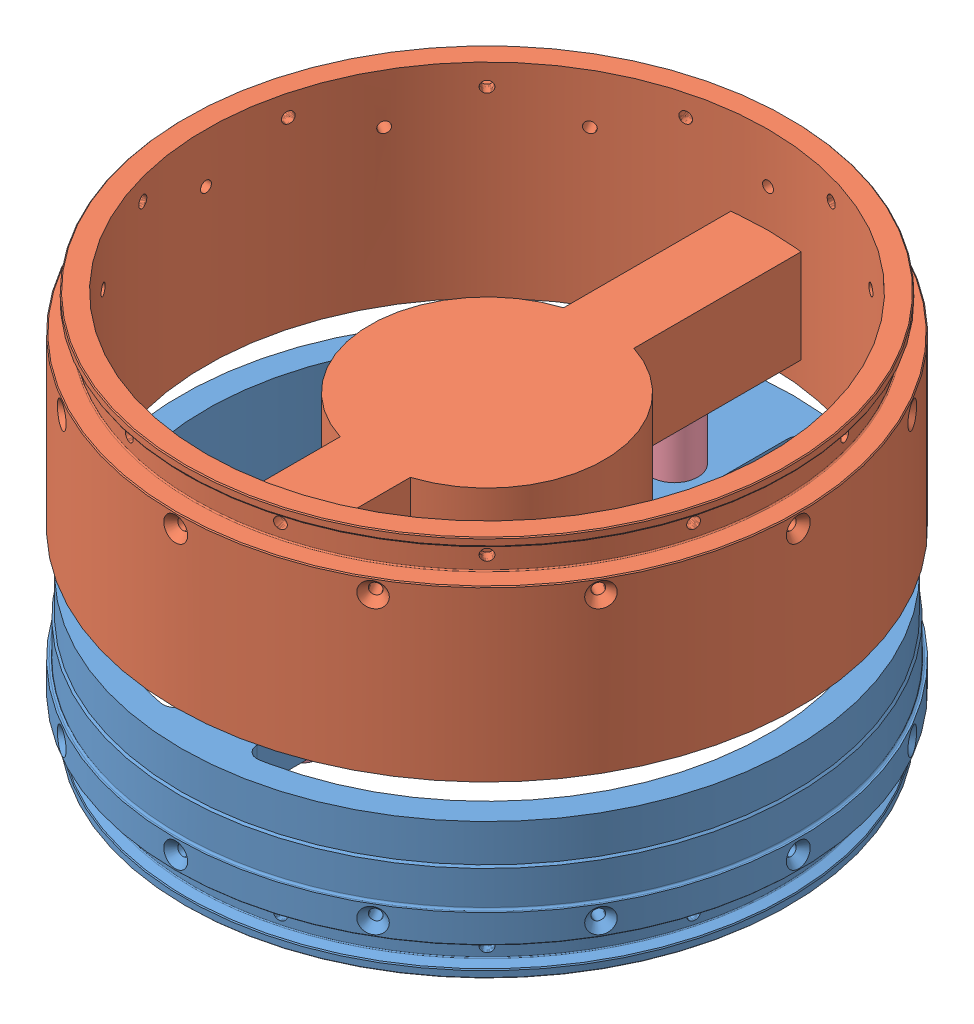
SolidWorks assembly Concept_Ring, configuration Default. Lengths in mm.
Overall size (168.91 103.49 168.91).
5 component instances, 4 part files, 8 mates.
Components (placement in the parent):
- Concept_Upper-1: Concept_Upper [Default] at (-11.1747 14.1513 -9.4137) size (168.91 37.68 168.91)
- Concept_Lower-1: Concept_Lower [Default] at (-11.1747 96.7282 -9.4137) x (-1 0 0) z (0 0 1) size (168.91 55.46 168.91)
- pretend_motor-1: pretend_motor [Default] at (-11.1747 77.1717 -9.4137) x (-0.757863 0 0.652414) z (0 1 0) size (38.1 38.1 55.13)
- Alignment_Pins-1: Alignment_Pins [Default] at (-11.1747 26.3217 -60.2137) size (12.7 50.8 12.7)
- Alignment_Pins-2: Alignment_Pins [Default] at (-11.1747 26.3217 41.3863) size (12.7 50.8 12.7)
Mates (geometry in assembly coordinates):
- Coincident1: coincident: circle of Concept_Lower-1; circle of pretend_motor-1
- Concentric1: concentric: cylinder of Concept_Lower-1 through (-11.1747 77.1217 -9.4137) axis (0 -1 0) radius 19.05; cylinder of pretend_motor-1 through (-11.1747 77.1217 -9.4137) axis (0 -1 0) radius 19.05
- Coincident2: coincident: circle of Concept_Lower-1; plane of Alignment_Pins-2 through (-11.1747 77.1217 41.3863) normal (0 1 0)
- Concentric3: concentric: cylinder of Concept_Lower-1 through (-11.1747 77.1217 41.3863) axis (0 -1 0) radius 6.35; cylinder of Alignment_Pins-2 through (-11.1747 77.1217 41.3863) axis (0 -1 0) radius 6.35
- Coincident3: coincident: plane of Concept_Lower-1 through (-11.1747 77.1217 -60.2137) normal (0 -1 0); plane of Alignment_Pins-1 through (-11.1747 77.1217 -60.2137) normal (0 1 0)
- Concentric4: concentric: cylinder of Concept_Lower-1 through (-11.1747 77.1217 -60.2137) axis (0 -1 0) radius 6.35; cylinder of Alignment_Pins-1 through (-11.1747 77.1217 -60.2137) axis (0 -1 0) radius 6.35
- Concentric5: concentric: cylinder of Concept_Upper-1 through (-11.1747 59.9198 41.3863) axis (0 -1 0) radius 6.35; cylinder of Alignment_Pins-2 through (-11.1747 77.1217 41.3863) axis (0 -1 0) radius 6.35
- Concentric6: concentric: cylinder of Concept_Upper-1 through (-11.1747 59.9198 -60.2137) axis (0 -1 0) radius 6.35; cylinder of Alignment_Pins-1 through (-11.1747 77.1217 -60.2137) axis (0 -1 0) radius 6.35
